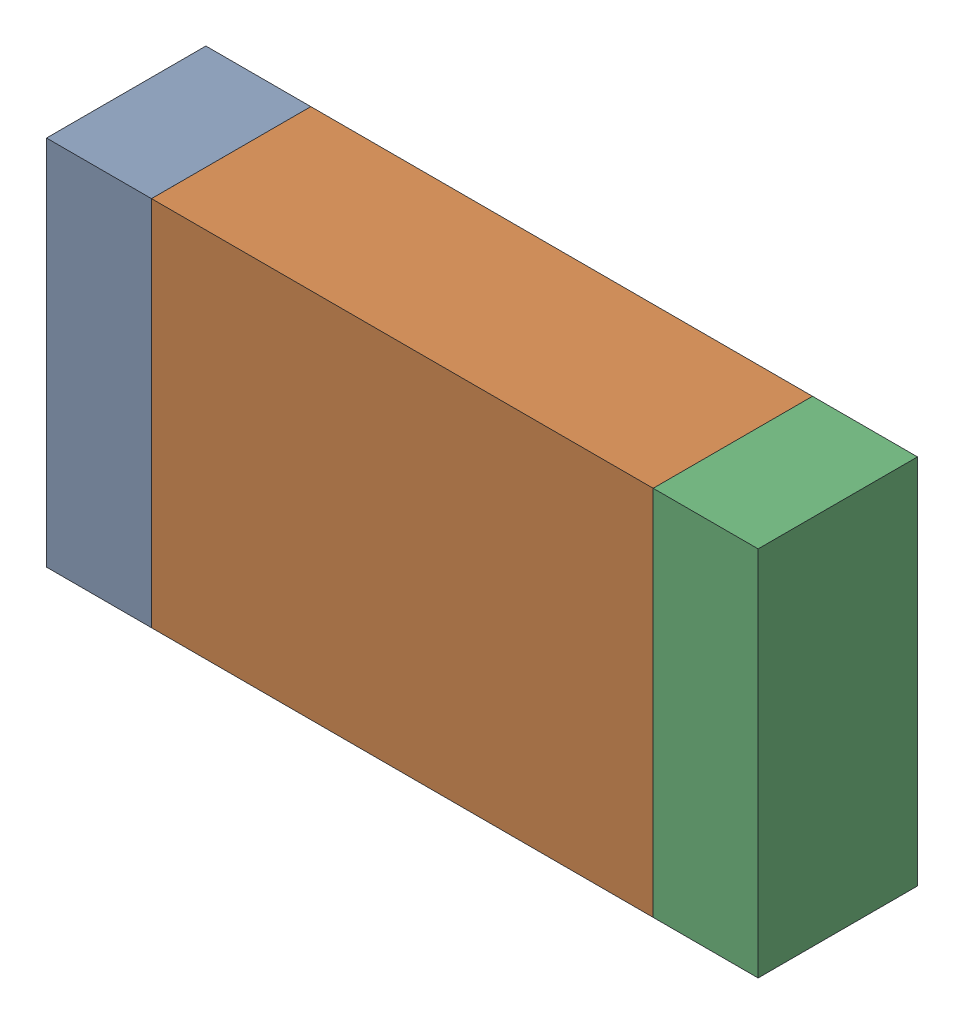
SolidWorks assembly R10-1, configuration Default. Lengths in mm.
Overall size (3.35 1.75 0.75).
6 component instances, 2 part files, 0 mates.
Components (placement in the parent):
- 959206760-1-1: 959206760-1 [Default] at (152.7506 83.5661 0) size (0.49 1.75 0.75)
  - Extruded-33-1: Extruded-33 [Default] at origin size (0.49 1.75 0.75)
- 959206896-1-1: 959206896-1 [Default] at (154.1781 83.5661 0) size (2.36 1.75 0.75)
  - Extruded-34-1: Extruded-34 [Default] at origin size (2.36 1.75 0.75)
- 959206760-1-2: 959206760-1 [Default] at (155.6056 83.5661 0) size (0.49 1.75 0.75)
  - Extruded-33-1: Extruded-33 [Default] at origin size (0.49 1.75 0.75)
